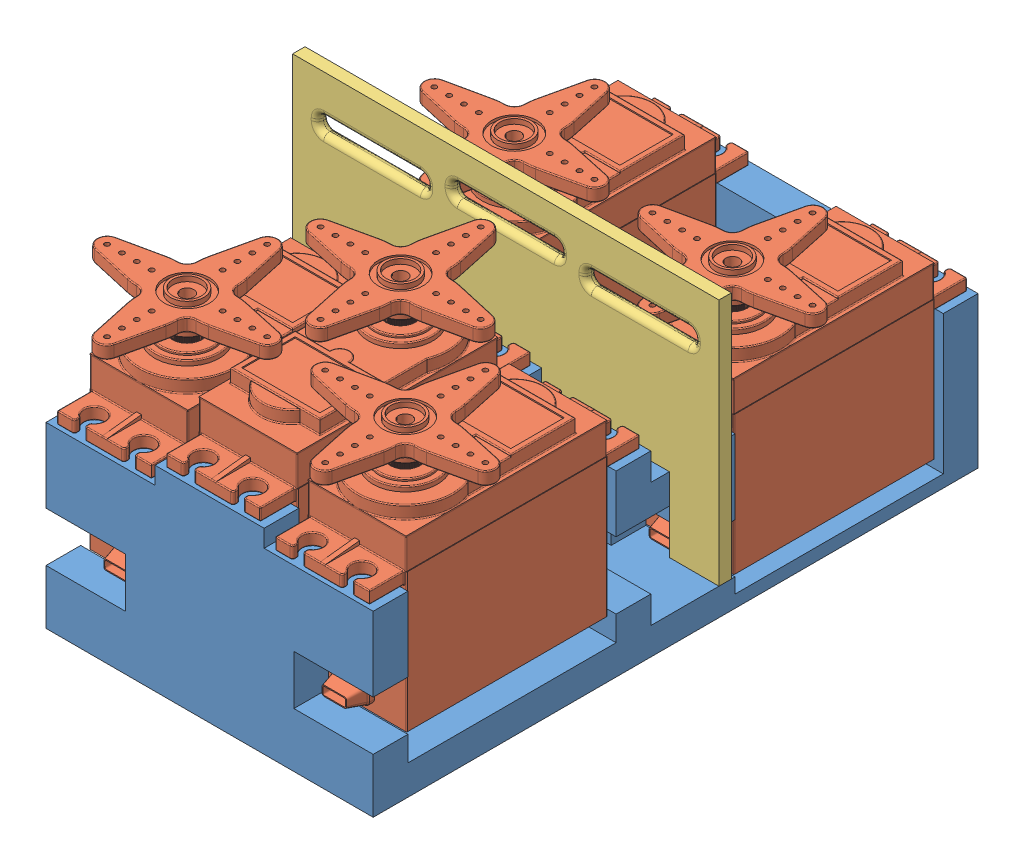
SolidWorks assembly Servo Assembly, configuration Default. Lengths in mm.
Overall size (86 65.5 122.79).
7 component instances, 3 part files, 19 mates.
Components (placement in the parent):
- Bed-1: Bed [Default] at (2.1207 32.6668 137.6174) size (66 39.5 122)
- S3003-2: S3003 [Default] at (35.1207 44.6668 109.6174) x (0 0 -1) z (1 0 0) size (56.04 47.8 36.5)
- S3003-3: S3003 [Default] at (13.1207 41.1668 109.6174) x (0 0 1) z (-1 0 0) size (56.04 47.8 36.5)
- S3003-4: S3003 [Default] at (57.1207 41.1668 109.6174) x (0 0 1) z (-1 0 0) size (56.04 47.8 36.5)
- S3003-5: S3003 [Default] at (13.1207 35.6668 43.6174) x (0 0 1) z (-1 0 0) size (56.04 47.8 36.5)
- S3003-6: S3003 [Default] at (57.1207 35.6668 43.6174) x (0 0 1) z (-1 0 0) size (56.04 47.8 36.5)
- String holder-2: String holder [Default] at (2.1207 60.1668 75.3674) x (1 0 0) z (0 -1 0) size (86 2.5 50)
Mates (geometry in assembly coordinates):
- Concentric3: concentric anti-aligned: circle of Bed - Copy-1; circle of S3003-2
- Concentric4: concentric anti-aligned: circle of Bed - Copy-1; circle of S3003-2
- Coincident3: coincident anti-aligned: plane of Bed-1 through (2.1207 72.1668 137.6174) normal (0 1 0); plane of S3003-2 through (35.1207 72.1668 109.6174) normal (0 -1 0)
- Concentric5: concentric anti-aligned: circle of Bed - Copy-1; circle of S3003-3
- Concentric6: concentric anti-aligned: circle of Bed - Copy-1; circle of S3003-3
- Coincident4: coincident anti-aligned: plane of Bed-1 through (2.1207 68.6668 137.6174) normal (0 1 0); plane of S3003-3 through (13.1207 68.6668 109.6174) normal (0 -1 0)
- Concentric7: concentric anti-aligned: circle of Bed - Copy-1; circle of S3003-4
- Concentric8: concentric anti-aligned: circle of Bed - Copy-1; circle of S3003-4
- Coincident5: coincident anti-aligned: plane of Bed-1 through (2.1207 68.6668 137.6174) normal (0 1 0); plane of S3003-4 through (57.1207 68.6668 109.6174) normal (0 -1 0)
- Concentric9: concentric anti-aligned: circle of Bed - Copy-1; circle of S3003-5
- Concentric10: concentric anti-aligned: circle of Bed - Copy-1; circle of S3003-5
- Coincident6: coincident anti-aligned: plane of Bed-1 through (2.1207 63.1668 -50.3826) normal (0 1 0); plane of S3003-5 through (13.1207 63.1668 43.6174) normal (0 -1 0)
- Concentric11: concentric anti-aligned: circle of Bed - Copy-1; circle of S3003-6
- Concentric12: concentric anti-aligned: circle of Bed - Copy-1; circle of S3003-6
- Coincident7: coincident anti-aligned: plane of Bed-1 through (2.1207 63.1668 -50.3826) normal (0 1 0); plane of S3003-6 through (57.1207 63.1668 43.6174) normal (0 -1 0)
- Coincident8: coincident anti-aligned: plane of Bed-1 through (2.1207 60.1668 137.6174) normal (0 1 0); plane of String holder-2 through (2.1207 60.1668 77.8674) normal (0 -1 0)
- Coincident9: coincident anti-aligned: plane of Bed-1 through (2.1207 60.1668 137.6174) normal (0 1 0); plane of String holder-2 through (2.1207 60.1668 77.8674) normal (0 -1 0)
- Coincident10: coincident anti-aligned: line of Bed-1 through (68.1207 60.1668 75.3674) axis (-1 0 0); line of String holder-2 through (2.1207 60.1668 75.3674) axis (1 0 0)
- Coincident11: coincident anti-aligned: plane of Bed-1 through (2.1207 38.6668 137.6174) normal (-1 0 0); plane of String holder-2 through (2.1207 60.1668 75.3674) normal (1 0 0)
